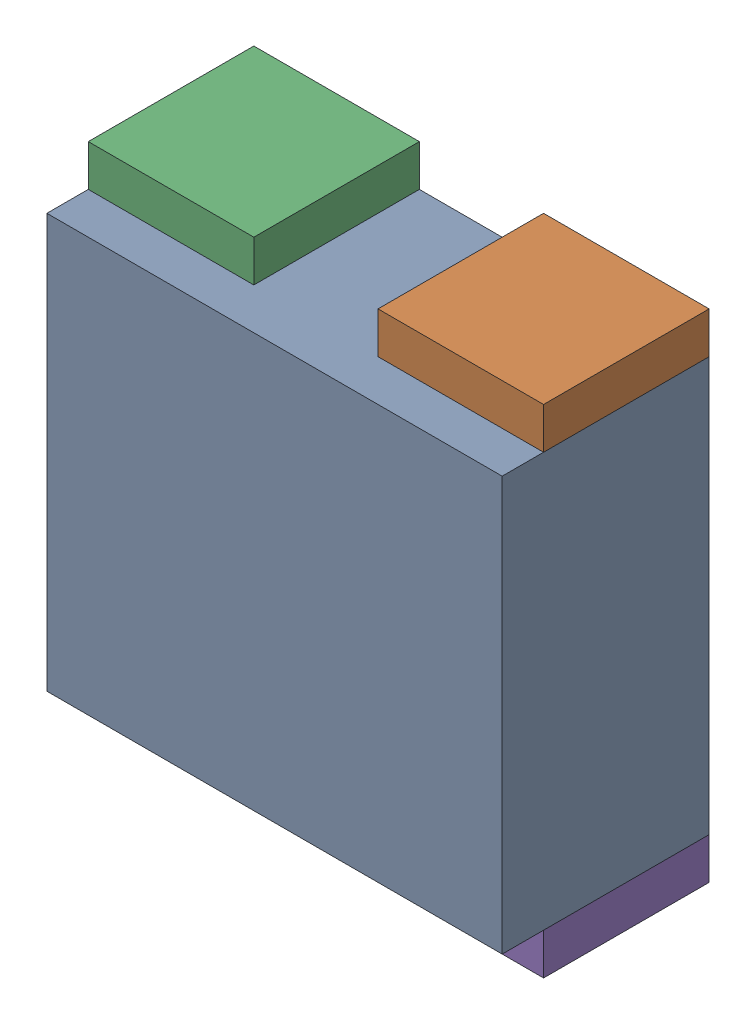
SolidWorks assembly RN20, configuration Default. Lengths in mm.
Overall size (1.1 1.2 0.5).
10 component instances, 2 part files, 0 mates.
Components (placement in the parent):
- 810156720-1: 810156720 [Default] at (118.4 76.35 0) size (1.1 1 0.5)
  - Extruded_13-1: Extruded_13 [Default] at origin size (1.1 1 0.5)
- 810157616-1: 810157616 [Default] at (118.75 76.9 0) size (0.4 0.1 0.4)
  - Extruded_12-1: Extruded_12 [Default] at origin size (0.4 0.1 0.4)
- 810157616-2: 810157616 [Default] at (118.05 76.9 0) size (0.4 0.1 0.4)
  - Extruded_12-1: Extruded_12 [Default] at origin size (0.4 0.1 0.4)
- 810157616-3: 810157616 [Default] at (118.05 75.8 0) size (0.4 0.1 0.4)
  - Extruded_12-1: Extruded_12 [Default] at origin size (0.4 0.1 0.4)
- 810157616-4: 810157616 [Default] at (118.75 75.8 0) size (0.4 0.1 0.4)
  - Extruded_12-1: Extruded_12 [Default] at origin size (0.4 0.1 0.4)
